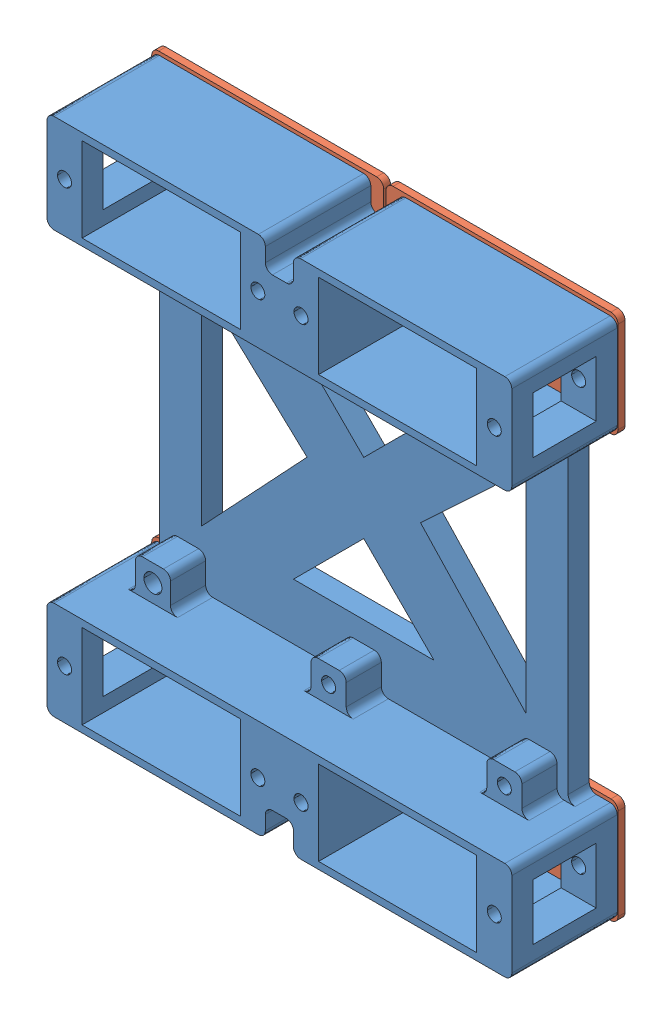
SolidWorks assembly BodyH, configuration Default. Lengths in mm.
Overall size (66.34 74.98 18.8).
5 component instances, 2 part files, 11 mates.
Components (placement in the parent):
- body2-1: body2 [Default] at (87.7945 -293.2121 -27.1921) size (66.14 73.98 15)
- hinge1-1: hinge1 [Default] at (2.8364 9.7381 52.8079) x (1 0.000279 0) z (0 0 -1) size (33 15 3.8)
- hinge1-2: hinge1 [Default] at (2.8364 69.7173 52.8079) x (1 0 0) z (0 0 -1) size (33 15 3.8)
- hinge1-3: hinge1 [Default] at (36.179 9.7342 52.8079) x (-1 0 0) z (0 0 -1) size (33 15 3.8)
- hinge1-4: hinge1 [Default] at (36.179 69.7173 52.8079) x (-1 0 0) z (0 0 -1) size (33 15 3.8)
Mates (geometry in assembly coordinates):
- Coincident3: coincident anti-aligned: cylinder of body2-1 through (-11.0636 9.7342 52.8079) axis (0 0 1) radius 1; circle of hinge1-1
- Coincident4: coincident anti-aligned: plane of body2-1 through (87.7945 -293.2121 52.8079) normal (0 0 -1); plane of hinge1-1 through (18.3382 3.2424 52.8079) normal (0 0 1)
- Coincident5: coincident anti-aligned: plane of body2-1 through (87.7945 -293.2121 52.8079) normal (0 0 -1); plane of hinge1-2 through (18.3364 63.2173 52.8079) normal (0 0 1)
- Concentric1: concentric aligned: cylinder of body2-1 through (-11.0636 69.7173 52.8079) axis (0 0 1) radius 1; cylinder of hinge1-2 through (-11.0636 69.7173 51.8079) axis (0 0 1) radius 1
- Concentric2: concentric aligned: cylinder of body2-1 through (16.4364 69.7173 52.8079) axis (0 0 1) radius 1; cylinder of hinge1-2 through (16.4364 69.7173 51.8079) axis (0 0 1) radius 1
- Coincident8: coincident anti-aligned: plane of body2-1 through (87.7945 -293.2121 52.8079) normal (0 0 -1); plane of hinge1-3 through (20.679 16.2342 52.8079) normal (0 0 1)
- Concentric4: concentric aligned: cylinder of body2-1 through (50.079 9.7342 52.8079) axis (0 0 1) radius 1; cylinder of hinge1-3 through (50.079 9.7342 51.8079) axis (0 0 1) radius 1
- Concentric5: concentric aligned: cylinder of body2-1 through (22.579 9.7342 52.8079) axis (0 0 1) radius 1; cylinder of hinge1-3 through (22.579 9.7342 51.8079) axis (0 0 1) radius 1
- Coincident11: coincident: plane of body2-1 through (87.7945 -293.2121 52.8079) normal (0 0 -1); plane of hinge1-4 through (20.679 76.2173 52.8079) normal (0 0 1)
- Concentric6: concentric: cylinder of body2-1 through (50.079 69.7173 52.8079) axis (0 0 1) radius 1; cylinder of hinge1-4 through (50.079 69.7173 51.8079) axis (0 0 1) radius 1
- Concentric7: concentric aligned: cylinder of body2-1 through (22.579 69.7173 52.8079) axis (0 0 1) radius 1; cylinder of hinge1-4 through (22.579 69.7173 51.8079) axis (0 0 1) radius 1
